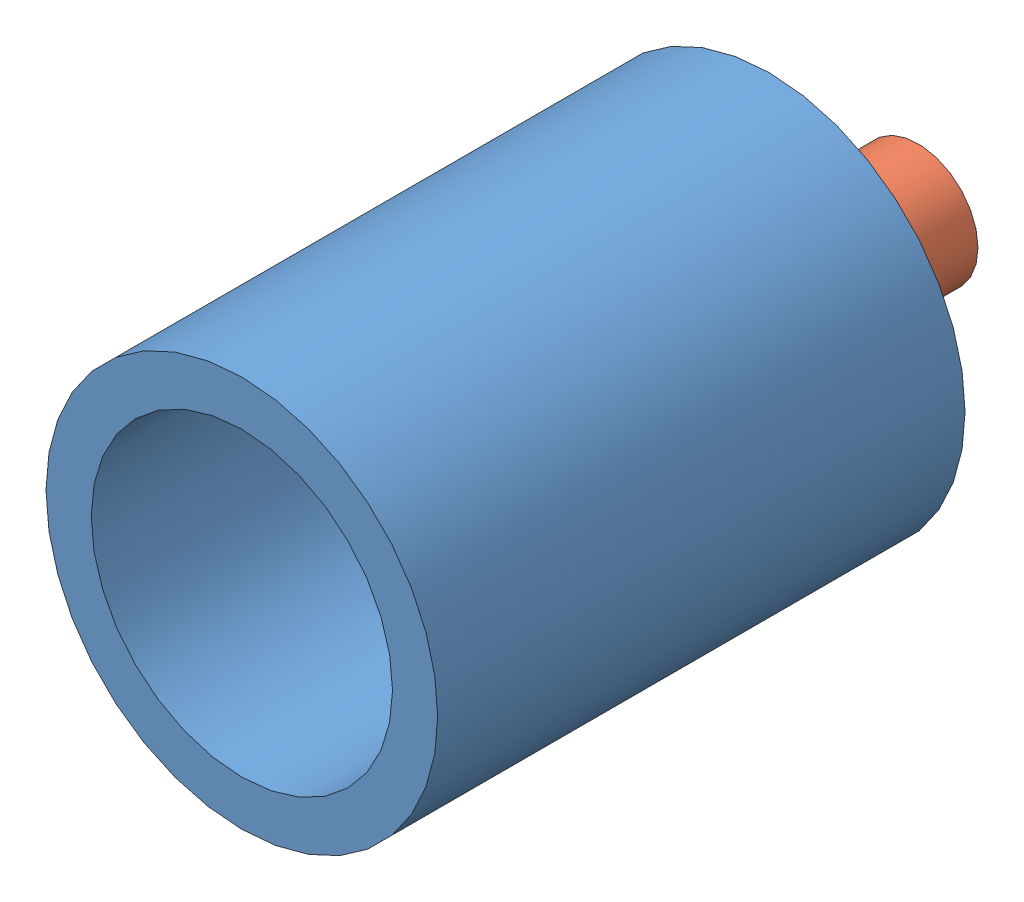
SolidWorks assembly assem3, configuration Default. Lengths in mm.
Overall size (26 26 44.86).
2 component instances, 2 part files, 1 mates.
Components (placement in the parent):
- cannon2-1: cannon2 [Default] at (5.2175 24.7365 13.1686) size (26 26 35)
- cannon3-1: cannon3 [Default] at (5.2175 24.7365 13.3102) size (19.9 19.9 15)
Mates (geometry in assembly coordinates):
- Concentric3: concentric anti-aligned: cylinder of cannon2-1 through (5.2175 24.7365 48.1686) axis (0 0 -1) radius 10; circle of cannon3-1
